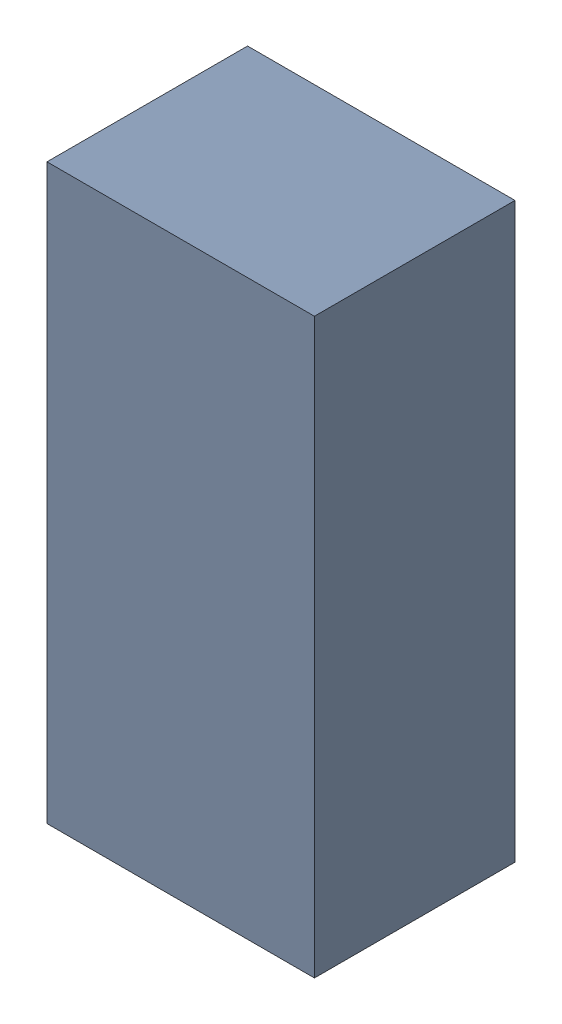
SolidWorks assembly U5Kanaloa_v2.0.0_Power_1, configuration Default. Lengths in mm.
Overall size (1.4 3 1.05).
2 component instances, 1 part files, 0 mates.
Components (placement in the parent):
- 378153920-1: 378153920 [Default] at (89.575 35.725 -2.2024) size (1.4 3 1.05)
  - Extruded_25-1: Extruded_25 [Default] at origin size (1.4 3 1.05)
